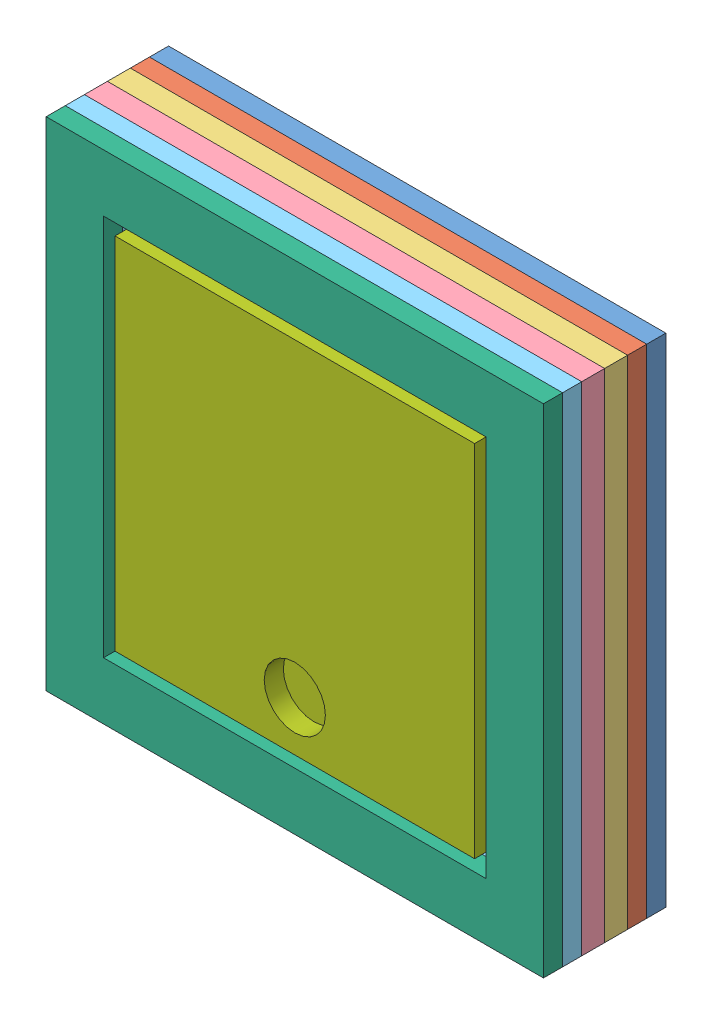
SolidWorks assembly Assieme1 LAMPADA FAB LAB, configuration Default. Lengths in mm.
Overall size (130 130 32).
7 component instances, 7 part files, 17 mates.
Components (placement in the parent):
- Parte6-2: Parte6 [Default] at (5.6778 -2.7297 127.5) size (130 130 5)
- strato5-2: strato5 [Default] at (5.6778 -2.7297 132.5) size (130 130 5)
- strato4 - Copia-1: strato4 - Copia [Default] at (5.6778 -2.7297 137.5) size (130 130 6)
- strato3-1: strato3 [Default] at (5.6778 -2.7297 143.5) size (130 130 6)
- strato 2-1: strato 2 [Default] at (5.6778 -2.7297 149.5) size (130 130 5)
- strato 1-1: strato 1 [Default] at (5.6778 -2.7297 154.5) size (130 130 5)
- plex-2: plex [Default] at (5.6778 -2.7297 149.5) size (94 94 10)
Mates (geometry in assembly coordinates):
- Coincidente4: coincident anti-aligned: plane of Parte6-2 through (5.6778 -2.7297 132.5) normal (0 0 1); plane of strato5-2 through (5.6778 -2.7297 132.5) normal (0 0 -1)
- Coincidente5: coincident aligned: plane of Parte6-2 through (70.6778 -67.7297 132.5) normal (1 0 0); plane of strato5-2 through (70.6778 -67.7297 137.5) normal (1 0 0)
- Coincidente6: coincident aligned: plane of Parte6-2 through (70.6778 62.2703 132.5) normal (0 1 0); plane of strato5-2 through (70.6778 62.2703 137.5) normal (0 1 0)
- Coincidente7: coincident anti-aligned: plane of strato5-2 through (5.6778 -2.7297 137.5) normal (0 0 1); plane of strato4 - Copia-1 through (5.6778 -2.7297 137.5) normal (0 0 -1)
- Coincidente8: coincident aligned: plane of strato5-2 through (70.6778 -67.7297 137.5) normal (1 0 0); plane of strato4 - Copia-1 through (70.6778 -67.7297 143.5) normal (1 0 0)
- Coincidente9: coincident aligned: plane of strato5-2 through (70.6778 62.2703 137.5) normal (0 1 0); plane of strato4 - Copia-1 through (70.6778 62.2703 143.5) normal (0 1 0)
- Coincidente10: coincident aligned: plane of strato4 - Copia-1 through (70.6778 62.2703 143.5) normal (0 1 0); plane of strato3-1 through (70.6778 62.2703 149.5) normal (0 1 0)
- Coincidente11: coincident anti-aligned: plane of strato4 - Copia-1 through (5.6778 -2.7297 143.5) normal (0 0 1); plane of strato3-1 through (5.6778 -2.7297 143.5) normal (0 0 -1)
- Coincidente12: coincident aligned: plane of strato4 - Copia-1 through (70.6778 -67.7297 143.5) normal (1 0 0); plane of strato3-1 through (70.6778 -67.7297 149.5) normal (1 0 0)
- Coincidente13: coincident anti-aligned: plane of strato3-1 through (5.6778 -2.7297 149.5) normal (0 0 1); plane of strato 2-1 through (5.6778 -2.7297 149.5) normal (0 0 -1)
- Coincidente14: coincident aligned: plane of strato3-1 through (70.6778 62.2703 149.5) normal (0 1 0); plane of strato 2-1 through (70.6778 62.2703 154.5) normal (0 1 0)
- Coincidente15: coincident aligned: plane of strato3-1 through (70.6778 -67.7297 149.5) normal (1 0 0); plane of strato 2-1 through (70.6778 62.2703 154.5) normal (1 0 0)
- Coincidente16: coincident aligned: plane of strato 2-1 through (70.6778 62.2703 154.5) normal (1 0 0); plane of strato 1-1 through (70.6778 62.2703 159.5) normal (1 0 0)
- Coincidente17: coincident anti-aligned: plane of strato 2-1 through (5.6778 -2.7297 154.5) normal (0 0 1); plane of strato 1-1 through (5.6778 -2.7297 154.5) normal (0 0 -1)
- Coincidente18: coincident aligned: plane of strato 2-1 through (70.6778 62.2703 154.5) normal (0 1 0); plane of strato 1-1 through (70.6778 62.2703 159.5) normal (0 1 0)
- Coincidente23: coincident anti-aligned: plane of strato3-1 through (5.6778 -2.7297 149.5) normal (0 0 1); plane of plex-2 through (-163.3765 -35.4078 149.5) normal (0 0 -1)
- Coincidente24: coincident: point of ?
